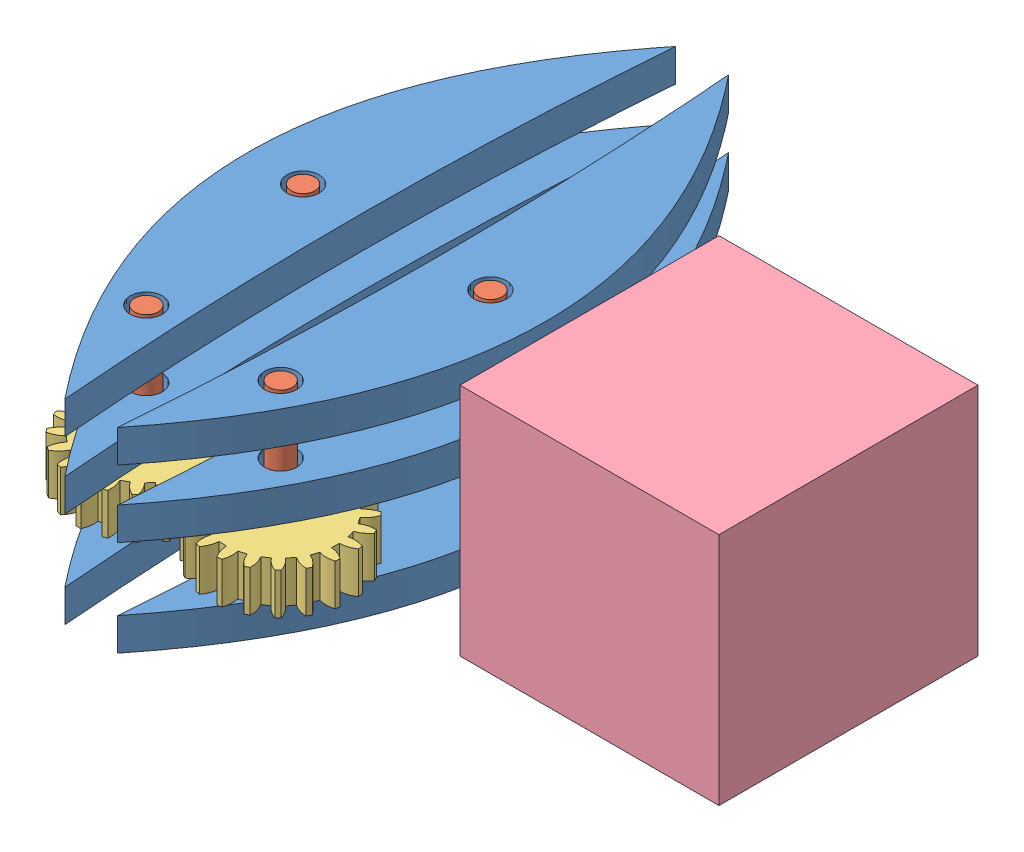
SolidWorks assembly Claw, configuration Default. Lengths in mm.
Overall size (74.61 28.8 75.23).
13 component instances, 4 part files, 34 mates.
Components (placement in the parent):
- Claw pincer left-1: Claw pincer left [Default] at (33.618 22.8769 24.4102) size (15 4 75)
- Claw pincer left-2: Claw pincer left [Default] at (33.618 14.6269 24.4102) size (15 4 75)
- Claw pincer left-3: Claw pincer left [Default] at (33.618 2.8769 24.4102) size (15 4 75)
- Claw pincer left-4: Claw pincer left [Default] at (-6.3157 26.8769 24.6429) x (-1 0 0) z (0 0 1) size (15 4 75)
- Rod-1: Rod [Default] at (25.0341 2.8769 6.7558) size (2.9 24 2.9)
- Claw pincer left-5: Claw pincer left [Default] at (-6.3157 6.8769 24.6429) x (-1 0 0) z (0 0 1) size (15 4 75)
- Claw pincer left-6: Claw pincer left [Default] at (-6.3157 18.6269 24.6429) x (-1 0 0) z (0 0 1) size (15 4 75)
- Rod-2: Rod [Default] at (2.2683 2.8769 6.9885) size (2.9 24 2.9)
- spur gear_ai-1: spur gear_ai [Inch - Spur gear 32DP 20T 14.5PA 0.2FW ---S20N3.0H2.0L0.03125N] at (5.5183 7.7969 29.4885) x (0 1 0) z (0.20201 0 0.979383) size (5.08 17.33 17.33)
- spur gear_ai-2: spur gear_ai [Inch - Spur gear 32DP 20T 14.5PA 0.2FW ---S20N3.0H2.0L0.03125N] at (21.7841 7.7969 29.2558) x (0 1 0) z (-0.958893 0 0.283767) size (5.08 17.33 17.33)
- Rod-4: Rod [Default] at (5.5183 2.8769 29.4885) size (2.9 24 2.9)
- Rod-5: Rod [Default] at (21.7841 2.8769 29.2558) x (0.999154 0 -0.041114) z (0.041114 0 0.999154) size (2.9 24 2.9)
- Block-1: Block [Default] at (53.9945 2.8769 7.6504) size (31.8 28.8 31.8)
Mates (geometry in assembly coordinates):
- Concentric1: concentric anti-aligned: circle of Claw pincer left-4; circle of Rod-4
- Coincident1: coincident aligned: plane of Claw pincer left-4 through (-4.4817 26.8769 6.9885) normal (0 1 0); plane of Rod-4 through (5.5183 26.8769 29.4885) normal (0 1 0)
- Concentric4: concentric anti-aligned: cylinder of spur gear_ai-1; cylinder of Rod-4 through (5.5183 26.8769 29.4885) axis (0 -1 0) radius 1.45
- Distance1: distance = 6 mm aligned: plane of spur gear_ai-1 through (5.5183 12.8769 29.4885) normal (0 1 0); plane of Claw pincer left-5 through (-4.4817 6.8769 6.9885) normal (0 1 0)
- Coincident3: coincident aligned: plane of Claw pincer left-1 through (31.7841 26.8769 6.7558) normal (0 1 0); plane of Rod-5 through (21.7841 26.8769 29.2558) normal (0 1 0)
- Concentric5: concentric anti-aligned: circle of Claw pincer left-1; cylinder of Rod-5 through (21.7841 26.8769 29.2558) axis (0 -1 0) radius 1.45
- Concentric6: concentric anti-aligned: circle of Claw pincer left-2; cylinder of Rod-5 through (21.7841 26.8769 29.2558) axis (0 -1 0) radius 1.45
- Concentric7: concentric aligned: circle of Claw pincer left-3; circle of Rod-5
- Coincident4: coincident aligned: plane of Claw pincer left-3 through (31.7841 2.8769 6.7558) normal (0 -1 0); plane of Rod-5 through (21.7841 2.8769 29.2558) normal (0 -1 0)
- Coincident5: coincident aligned: plane of spur gear_ai-1 through (5.5183 12.8769 29.4885) normal (0 1 0); plane of spur gear_ai-2 through (21.7841 12.8769 29.2558) normal (0 1 0)
- Concentric9: concentric anti-aligned: circle of spur gear_ai-2; cylinder of Rod-5 through (21.7841 26.8769 29.2558) axis (0 -1 0) radius 1.45
- Parallel1: parallel aligned: line of Claw pincer left-4 through (10.5183 22.8769 44.4885) axis (0 1 0); line of Claw pincer left-6 through (10.5183 14.6269 44.4885) axis (0 1 0)
- Coincident7: coincident aligned: plane of Claw pincer left-3 through (31.7841 2.8769 6.7558) normal (0 -1 0); plane of Claw pincer left-5 through (-4.4817 2.8769 6.9885) normal (0 -1 0)
- Parallel2: parallel aligned: line of Claw pincer left-1 through (16.7841 26.8769 44.2558) axis (0 -1 0); line of Claw pincer left-2 through (16.7841 18.6269 44.2558) axis (0 -1 0)
- Parallel3: parallel aligned: line of Claw pincer left-2 through (16.7841 18.6269 44.2558) axis (0 -1 0); line of Claw pincer left-3 through (16.7841 6.8769 44.2558) axis (0 -1 0)
- Parallel4: parallel aligned: line of Claw pincer left-5 through (10.5183 2.8769 44.4885) axis (0 1 0); line of Claw pincer left-6 through (10.5183 14.6269 44.4885) axis (0 1 0)
- Parallel5: parallel aligned: plane of Claw pincer left-1 through (31.7841 26.8769 6.7558) normal (0 1 0); plane of Claw pincer left-4 through (-4.4817 26.8769 6.9885) normal (0 1 0)
- Coincident13: coincident aligned: plane of Claw pincer left-2 through (31.7841 18.6269 6.7558) normal (0 1 0); plane of Claw pincer left-6 through (-4.4817 18.6269 6.9885) normal (0 1 0)
- Coincident14: coincident aligned: plane of Claw pincer left-3 through (31.7841 6.8769 6.7558) normal (0 1 0); plane of Claw pincer left-5 through (-4.4817 6.8769 6.9885) normal (0 1 0)
- Parallel7: parallel anti-aligned: line of Claw pincer left-1 through (16.7841 26.8769 44.2558) axis (0 -1 0); line of Claw pincer left-4 through (10.5183 22.8769 44.4885) axis (0 1 0)
- Parallel8: parallel: face of Claw pincer left-1; face of Claw pincer left-2
- Coincident16: coincident aligned: plane of Claw pincer left-1 through (31.7841 26.8769 6.7558) normal (0 1 0); plane of Rod-1 through (25.0341 26.8769 6.7558) normal (0 1 0)
- Concentric10: concentric aligned: circle of Claw pincer left-1; circle of Rod-1
- Concentric11: concentric anti-aligned: circle of Claw pincer left-2; cylinder of Rod-1 through (25.0341 26.8769 6.7558) axis (0 -1 0) radius 1.45
- Concentric12: concentric anti-aligned: circle of Claw pincer left-3; cylinder of Rod-1 through (25.0341 26.8769 6.7558) axis (0 -1 0) radius 1.45
- Concentric13: concentric aligned: circle of Claw pincer left-6; cylinder of Rod-4 through (5.5183 26.8769 29.4885) axis (0 -1 0) radius 1.45
- Concentric14: concentric aligned: circle of Claw pincer left-5; cylinder of Rod-4 through (5.5183 26.8769 29.4885) axis (0 -1 0) radius 1.45
- Coincident17: coincident aligned: plane of Claw pincer left-5 through (-4.4817 2.8769 6.9885) normal (0 -1 0); plane of Rod-4 through (5.5183 2.8769 29.4885) normal (0 -1 0)
- Coincident18: coincident aligned: plane of Claw pincer left-4 through (-4.4817 26.8769 6.9885) normal (0 1 0); plane of Rod-2 through (2.2683 26.8769 6.9885) normal (0 1 0)
- Concentric15: concentric aligned: circle of Claw pincer left-4; cylinder of Rod-2 through (2.2683 26.8769 6.9885) axis (0 -1 0) radius 1.45
- Distance2: distance = 1.75 mm anti-aligned: plane of Claw pincer left-6 through (-4.4817 14.6269 6.9885) normal (0 -1 0); plane of spur gear_ai-1 through (5.5183 12.8769 29.4885) normal (0 1 0)
- Concentric16: concentric aligned: circle of Claw pincer left-6; cylinder of Rod-2 through (2.2683 26.8769 6.9885) axis (0 -1 0) radius 1.45
- Concentric17: concentric anti-aligned: circle of Claw pincer left-5; circle of Rod-2
- Coincident24: coincident aligned: plane of Claw pincer left-3 through (31.7841 2.8769 6.7558) normal (0 -1 0); plane of Block-1 through (53.9945 2.8769 7.6504) normal (0 -1 0)
